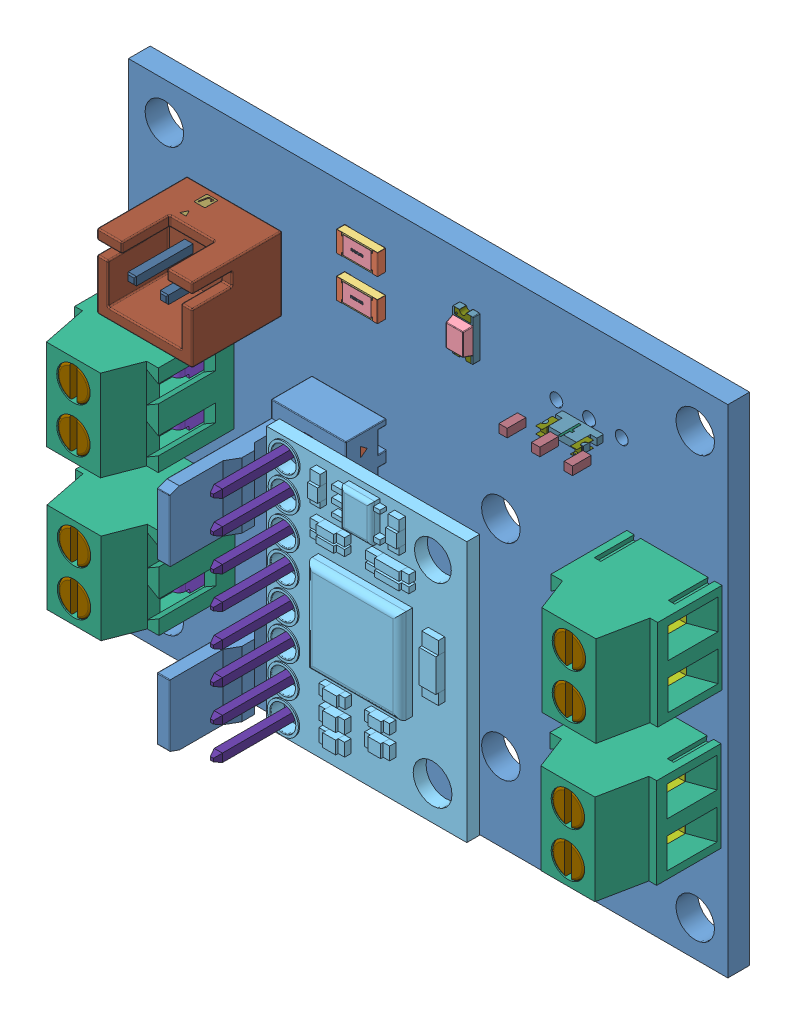
SolidWorks assembly Sensor_PCB.step, configuration Default. Lengths in mm.
Overall size (46.6 38.61 15.7).
76 component instances, 23 part files, 0 mates.
Components (placement in the parent):
- Board.step-1: Board.step [Default] at origin size (46.6 38.61 1.69)
  - Open CASCADE STEP translator 7.5 2.1.1.step-1: Open CASCADE STEP translator 7.5 2.1.1.step [Default] at (0 0 -1.6914) size (46.6 38.61 1.69)
- R2.step-1: R2.step [Default] at origin size (3.2 1.6 0.65)
  - Res_Rohm_MCR18ERTFL1R10_eec.step-1: Res_Rohm_MCR18ERTFL1R10_eec.step [Default] at (41.9058 56.261 0) size (3.2 1.6 0.65)
  - Res_Rohm_MCR18ERTFL1R10_eec-0.step-1: Res_Rohm_MCR18ERTFL1R10_eec-0.step [Default] at (41.9058 56.261 0) size (3.15 1.6 0.6)
  - Res_Rohm_MCR18ERTFL1R10_eec-1.step-1: Res_Rohm_MCR18ERTFL1R10_eec-1.step [Default] at (41.9058 56.261 0) size (2.2 1.38 0.02)
  - Res_Rohm_MCR18ERTFL1R10_eec-2.step-1: Res_Rohm_MCR18ERTFL1R10_eec-2.step [Default] at (41.9058 56.261 0) size (0.94 0.2 0.01)
- R1.step-1: R1.step [Default] at origin size (3.2 1.6 0.65)
  - Res_Rohm_MCR18ERTFL1R10_eec.step-1: Res_Rohm_MCR18ERTFL1R10_eec.step [Default] at (41.91 59.436 0) size (3.2 1.6 0.65)
  - Res_Rohm_MCR18ERTFL1R10_eec-0.step-1: Res_Rohm_MCR18ERTFL1R10_eec-0.step [Default] at (41.91 59.436 0) size (3.15 1.6 0.6)
  - Res_Rohm_MCR18ERTFL1R10_eec-1.step-1: Res_Rohm_MCR18ERTFL1R10_eec-1.step [Default] at (41.91 59.436 0) size (2.2 1.38 0.02)
  - Res_Rohm_MCR18ERTFL1R10_eec-2.step-1: Res_Rohm_MCR18ERTFL1R10_eec-2.step [Default] at (41.91 59.436 0) size (0.94 0.2 0.01)
- J7.step-1: J7.step [Default] at origin size (7.4 7.45 12.2)
  - 691214110002.step-1: 691214110002.step [Default] at (28.113 34.7951 3) x (0 -1 0) z (0 0 1) size (7.45 7.4 12.2)
    - 691214110002-12.step-1: 691214110002-12.step [Default] at origin size (7.45 7.4 8.5)
    - 6912141100xx_CAGE.step-1: 6912141100xx_CAGE.step [Default] at (1.725 -0.3 -0.125) size (2.6 3.95 4.15)
    - 6912141100xx_CAGE.step-2: 6912141100xx_CAGE.step [Default] at (-1.775 -0.3 -0.125) size (2.6 3.95 4.15)
    - 6912141100xx_PIN.step-1: 6912141100xx_PIN.step [Default] at (1.775 0.145 -1.2) x (1 0 0) z (0 1 0) size (2 7.15 4.8)
    - 6912141100xx_PIN.step-2: 6912141100xx_PIN.step [Default] at (-1.725 0.145 -1.2) x (1 0 0) z (0 1 0) size (2 7.15 4.8)
    - 6912141100xx_VIS.step-1: 6912141100xx_VIS.step [Default] at (1.725 -0.3 4.45) size (2.6 2.6 4.2)
    - 6912141100xx_VIS.step-2: 6912141100xx_VIS.step [Default] at (-1.775 -0.3 4.45) size (2.6 2.6 4.2)
- J6.step-1: J6.step [Default] at origin size (7.4 7.45 12.2)
  - 691214110002.step-1: 691214110002.step [Default] at (65.913 36.4239 3) x (0 1 0) z (0 0 1) size (7.45 7.4 12.2)
    - 691214110002-12.step-1: 691214110002-12.step [Default] at origin size (7.45 7.4 8.5)
    - 6912141100xx_CAGE.step-1: 6912141100xx_CAGE.step [Default] at (1.725 -0.3 -0.125) size (2.6 3.95 4.15)
    - 6912141100xx_CAGE.step-2: 6912141100xx_CAGE.step [Default] at (-1.775 -0.3 -0.125) size (2.6 3.95 4.15)
    - 6912141100xx_PIN.step-1: 6912141100xx_PIN.step [Default] at (1.775 0.145 -1.2) x (1 0 0) z (0 1 0) size (2 7.15 4.8)
    - 6912141100xx_PIN.step-2: 6912141100xx_PIN.step [Default] at (-1.725 0.145 -1.2) x (1 0 0) z (0 1 0) size (2 7.15 4.8)
    - 6912141100xx_VIS.step-1: 6912141100xx_VIS.step [Default] at (1.725 -0.3 4.45) size (2.6 2.6 4.2)
    - 6912141100xx_VIS.step-2: 6912141100xx_VIS.step [Default] at (-1.775 -0.3 4.45) size (2.6 2.6 4.2)
- J5.step-1: J5.step [Default] at origin size (7.4 5.75 10.4)
  - Conn_JST_B2B-XH-A_LF_SN_eec.step-1: Conn_JST_B2B-XH-A_LF_SN_eec.step [Default] at (31.75 54.483 0) size (7.4 5.75 10.4)
    - 1.step-1: 1.step [Default] at (0 0.025 0) x (-1 0 0) z (0 1 0) size (7.4 10.4 5.75)
      - 1-10.step-1: 1-10.step [Default] at origin size (3.14 10.2 0.64)
      - B2B-XH-A.step-1: B2B-XH-A.step [Default] at origin size (7.4 7 5.75)
      - JST Logo adjustable.step-1: JST Logo adjustable.step [Default] at (-1.7267 5.5034 2.841) size (0.85 2.3 0.01)
- J4.step-1: J4.step [Default] at origin size (5.73 0.88 3.68)
  - Conn_Molex_90120-0763_eec.step-1: Conn_Molex_90120-0763_eec.step [Default] at (59.309 56.642 0) x (-1 0 0) z (0 0 1) size (5.73 0.88 3.68)
    - 1-5.step-1: 1-5.step [Default] at (0 0 1.9) x (1 0 0) z (0 1 0) size (5.73 1.45 0.65)
    - 2.step-1: 2.step [Default] at (0 0 1.267) x (1 0 0) z (0 1 0) size (3.2 1.6 0.53)
    - 3.step-1: 3.step [Default] at (0 0 1.5) x (1 0 0) z (0 1 0) size (0.35 1.6 0.01)
    - 4.step-1: 4.step [Default] at (0 0 1.9) x (1 0 0) z (0 1 0) size (3.2 1.3 0.55)
- J3.step-1: J3.step [Default] at origin size (7.4 7.45 12.2)
  - 691214110002.step-1: 691214110002.step [Default] at (28.067 45.7451 3) x (0 -1 0) z (0 0 1) size (7.45 7.4 12.2)
    - 691214110002-12.step-1: 691214110002-12.step [Default] at origin size (7.45 7.4 8.5)
    - 6912141100xx_CAGE.step-1: 6912141100xx_CAGE.step [Default] at (1.725 -0.3 -0.125) size (2.6 3.95 4.15)
    - 6912141100xx_CAGE.step-2: 6912141100xx_CAGE.step [Default] at (-1.775 -0.3 -0.125) size (2.6 3.95 4.15)
    - 6912141100xx_PIN.step-1: 6912141100xx_PIN.step [Default] at (1.775 0.145 -1.2) x (1 0 0) z (0 1 0) size (2 7.15 4.8)
    - 6912141100xx_PIN.step-2: 6912141100xx_PIN.step [Default] at (-1.725 0.145 -1.2) x (1 0 0) z (0 1 0) size (2 7.15 4.8)
    - 6912141100xx_VIS.step-1: 6912141100xx_VIS.step [Default] at (1.725 -0.3 4.45) size (2.6 2.6 4.2)
    - 6912141100xx_VIS.step-2: 6912141100xx_VIS.step [Default] at (-1.775 -0.3 4.45) size (2.6 2.6 4.2)
- J2.step-1: J2.step [Default] at origin size (7.4 7.45 12.2)
  - 691214110002.step-1: 691214110002.step [Default] at (65.994 47.1199 3) x (0 1 0) z (0 0 1) size (7.45 7.4 12.2)
    - 691214110002-12.step-1: 691214110002-12.step [Default] at origin size (7.45 7.4 8.5)
    - 6912141100xx_CAGE.step-1: 6912141100xx_CAGE.step [Default] at (1.725 -0.3 -0.125) size (2.6 3.95 4.15)
    - 6912141100xx_CAGE.step-2: 6912141100xx_CAGE.step [Default] at (-1.775 -0.3 -0.125) size (2.6 3.95 4.15)
    - 6912141100xx_PIN.step-1: 6912141100xx_PIN.step [Default] at (1.775 0.145 -1.2) x (1 0 0) z (0 1 0) size (2 7.15 4.8)
    - 6912141100xx_PIN.step-2: 6912141100xx_PIN.step [Default] at (-1.725 0.145 -1.2) x (1 0 0) z (0 1 0) size (2 7.15 4.8)
    - 6912141100xx_VIS.step-1: 6912141100xx_VIS.step [Default] at (1.725 -0.3 4.45) size (2.6 2.6 4.2)
    - 6912141100xx_VIS.step-2: 6912141100xx_VIS.step [Default] at (-1.775 -0.3 4.45) size (2.6 2.6 4.2)
- J1.step-1: J1.step [Default] at origin size (5.8 20.32 15.61)
  - Conn_Molex_22-29-2081_eec.step-1: Conn_Molex_22-29-2081_eec.step [Default] at (40.66 38.608 0) x (0 1 0) z (0 0 1) size (20.32 5.8 15.61)
    - 22-29-2081.step-1: 22-29-2081.step [Default] at (0 0 1.58) size (20.32 5.8 15.61)
      - 1-6.step-1: 1-6.step [Default] x (1 0 0) z (0 -1 0) size (18.42 7.5 0.64)
      - 2-7.step-1: 2-7.step [Default] x (1 0 0) z (0 -1 0) size (18.42 4.2 0.64)
      - 3-8.step-1: 3-8.step [Default] x (1 0 0) z (0 -1 0) size (20.32 12.05 5.8)
    - Pin1_Triangle.step-1: Pin1_Triangle.step [Default] at (8.9165 -2.801 -1.5339) x (1 0 0) z (0 -1 0) size (0.78 0.53 0.01)
    - Molex.step-1: Molex.step [Default] at (-8.0974 -2.8986 1.9037) x (1 0 0) z (0 -1 0) size (2.43 0.6 0)
- D1.step-1: D1.step [Default] at origin size (1.6 3.2 1.2)
  - Diode_Broadcom_HSMG-C150_eec.step-1: Diode_Broadcom_HSMG-C150_eec.step [Default] at (50.038 57.912 0) x (0 -1 0) z (0 0 1) size (3.2 1.6 1.2)
    - 1-13.step-1: 1-13.step [Default] at origin size (2 1.6 0.66)
    - 2.step-1: 2.step [Default] at origin size (3.2 1.6 0.53)
    - 3.step-1: 3.step [Default] at origin size (0.35 1.6 0.01)
    - 4.step-1: 4.step [Default] at origin size (3.2 1.3 0.55)
- Free-Models.step-1: Free-Models.step [Default] at origin size (15.56 20.26 2)
  - MPU6050.step-1: MPU6050.step [Default] at (54.803 28.3501 5) x (1 0 0) z (0 -1 0) size (15.56 2 20.26)
